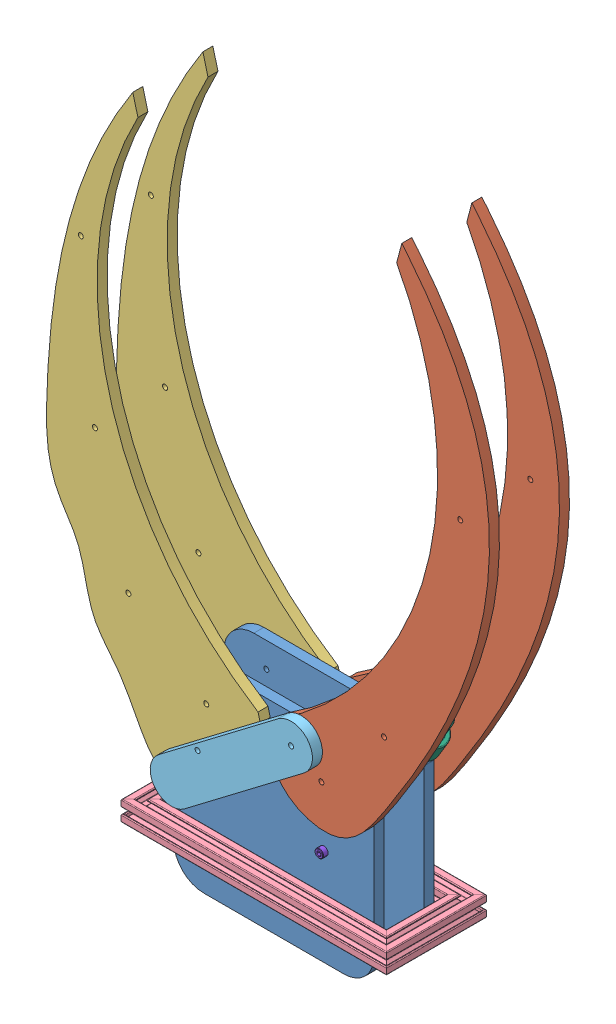
SolidWorks assembly claw complete, configuration Default. Lengths in mm.
Overall size (614.17 674.27 100).
12 component instances, 8 part files, 24 mates.
Components (placement in the parent):
- base (1)-1: base (1) [Default] at (84.5945 78.7634 160.6694) size (200 200 10)
- left-1: left [Default] at (97.6438 176.1538 100.6694) x (0.967017 -0.254711 0) z (0 0 1) size (196.08 572.16 10)
- right-1: right [Default] at (78.7753 172.5806 100.6694) x (0.966864 0.255292 0) z (0 0 1) size (173.08 567.26 10)
- base (1)-2: base (1) [Default] at (84.5945 78.7634 110.6694) size (200 200 10)
- right-2: right [Default] at (78.7753 172.5806 170.6694) x (0.966864 0.255292 0) z (0 0 1) size (173.08 567.26 10)
- left-2: left [Default] at (97.6438 176.1538 170.6694) x (0.967017 -0.254711 0) z (0 0 1) size (196.08 572.16 10)
- claw support-3: claw support [Default<As Machined>] at (84.5945 28.7634 140.6694) x (-1 0 0) z (0 1 0) size (265 100 20)
- claw motion-1: claw motion [Default] at (64.7629 126.4273 180.6694) x (0.79619 0.605047 0) z (0 0 1) size (192.73 42.73 10)
- cylinder assembly-1: cylinder assembly [Default] at (148.8168 100.0117 48.5018) x (0 0 -1) z (0.516333 0.856388 0) size (30 32.55 195)
  - cylinder-1: cylinder [Default] at (-92.1798 -0.5475 141.514) size (30 32.55 185)
  - cylinder rod-1: cylinder rod [Default] at (-92.1798 -0.5475 51.514) x (0.995961 0.089791 0) z (0.089791 -0.995961 0) size (10 100 10)
- socket head cap screw_am-1: socket head cap screw_am [B18.3.1M - 5 x 0.8 x 70 Hex SHCS -- 22NHX] at (134.5775 75.334 175.6694) x (0 0 -1) z (0.998896 -0.046986 0) size (75 8.5 8.5)
Mates (geometry in assembly coordinates):
- Distance3: distance = 40 mm aligned: plane of claw support-3 through (-37.9055 18.7634 184.4694) normal (0 -1 0); plane of base (1)-2 through (14.5945 -21.2366 120.6694) normal (0 -1 0)
- Concentric17: concentric aligned: cylinder of left-2 through (121.8192 169.786 180.6694) axis (0 0 -1) radius 2.5; cylinder of claw motion-1 through (121.8192 169.786 190.6694) axis (0 0 -1) radius 2.5
- Concentric18: concentric aligned: cylinder of right-2 through (28.4116 119.0557 180.6694) axis (0 0 -1) radius 2.5; cylinder of claw motion-1 through (28.4116 119.0557 190.6694) axis (0 0 -1) radius 2.5
- Coincident13: coincident anti-aligned: plane of right-2 through (262.9987 464.277 180.6694) normal (0 0 1); plane of claw motion-1 through (2.3907 79.029 180.6694) normal (0 0 -1)
- Coincident14: coincident anti-aligned: plane of left-2 through (289.7572 315.3858 180.6694) normal (0 0 1); plane of claw motion-1 through (2.3907 79.029 180.6694) normal (0 0 -1)
- Coincident15: coincident anti-aligned: plane of base (1)-1 through (14.5945 8.7634 170.6694) normal (0 0 1); plane of claw support-3 through (-37.9055 24.9634 170.6694) normal (0 0 -1)
- Coincident20: coincident anti-aligned: plane of base (1)-1 through (14.5945 8.7634 170.6694) normal (0 0 1); plane of left-2 through (289.7572 315.3858 170.6694) normal (0 0 -1)
- Concentric19: concentric aligned: cylinder of base (1)-1 through (142.0945 143.7634 170.6694) axis (0 0 -1) radius 2.5; cylinder of left-2 through (142.0945 143.7634 180.6694) axis (0 0 -1) radius 2.5
- Concentric20: concentric aligned: cylinder of base (1)-1 through (27.0945 153.7634 170.6694) axis (0 0 -1) radius 2.5; cylinder of right-2 through (27.0945 153.7634 180.6694) axis (0 0 -1) radius 2.5
- Concentric21: concentric aligned: cylinder of right-1 through (-50.7146 210.5898 110.6694) axis (0 0 -1) radius 2.5; cylinder of right-2 through (-50.7146 210.5898 180.6694) axis (0 0 -1) radius 2.5
- Concentric22: concentric aligned: cylinder of right-1 through (-84.1373 337.1715 110.6694) axis (0 0 -1) radius 2.5; cylinder of right-2 through (-84.1373 337.1715 180.6694) axis (0 0 -1) radius 2.5
- Concentric23: concentric aligned: cylinder of left-1 through (280.8661 439.9001 110.6694) axis (0 0 -1) radius 2.5; cylinder of left-2 through (280.8661 439.9001 180.6694) axis (0 0 -1) radius 2.5
- Concentric24: concentric aligned: cylinder of left-1 through (142.0945 143.7634 110.6694) axis (0 0 -1) radius 2.5; cylinder of base (1)-2 through (142.0945 143.7634 120.6694) axis (0 0 -1) radius 2.5
- Coincident23: coincident anti-aligned: plane of base (1)-2 through (14.5945 8.7634 110.6694) normal (0 0 -1); plane of claw support-3 through (-37.9055 37.9634 110.6694) normal (0 0 1)
- Width1: width anti-aligned: plane of claw support-3 through (197.0945 24.9634 180.6694) normal (-1 0 0); plane of claw support-3 through (-27.9055 24.9634 180.6694) normal (1 0 0); plane of base (1)-1 through (184.5945 8.7634 170.6694) normal (1 0 0); plane of base (1)-1 through (-15.4055 8.7634 170.6694) normal (-1 0 0)
- Concentric25: concentric aligned: cylinder of base (1)-1 through (134.5775 75.334 170.6694) axis (0 0 -1) radius 4; cylinder of base (1)-2 through (134.5775 75.334 120.6694) axis (0 0 -1) radius 4
- Concentric26: concentric aligned: cylinder of base (1)-1 through (134.5775 75.334 170.6694) axis (0 0 -1) radius 4; cylinder of cylinder assembly-1/cylinder-1 through (134.5775 75.334 155.6816) axis (0 0 -1) radius 4
- Width2: width aligned: plane of cylinder assembly-1/cylinder-1 through (134.5775 75.334 148.1816) normal (0 0 1); plane of cylinder assembly-1/cylinder-1 through (134.5775 75.334 133.1572) normal (0 0 -1); plane of base (1)-2 through (14.5945 8.7634 120.6694) normal (0 0 1); plane of base (1)-1 through (14.5945 8.7634 160.6694) normal (0 0 -1)
- Coincident24: coincident anti-aligned: plane of right-1 through (262.9987 464.277 110.6694) normal (0 0 1); plane of base (1)-2 through (14.5945 8.7634 110.6694) normal (0 0 -1)
- Coincident25: coincident anti-aligned: plane of left-1 through (289.7572 315.3858 110.6694) normal (0 0 1); plane of base (1)-2 through (14.5945 8.7634 110.6694) normal (0 0 -1)
- Concentric27: concentric anti-aligned: cylinder of base (1)-1 through (134.5775 75.334 170.6694) axis (0 0 -1) radius 4; cylinder of socket head cap screw_am-1 through (134.5775 75.334 207.4194) axis (0 0 1) radius 4.25
- Coincident26: coincident anti-aligned: plane of base (1)-1 through (14.5945 8.7634 170.6694) normal (0 0 1); plane of socket head cap screw_am-1 through (134.7772 79.5793 170.6694) normal (0 0 -1)
- Lock1: lock: unknown of cylinder assembly-1/cylinder-1; unknown of socket head cap screw_am-1
- Lock2: lock: unknown of base (1)-1; unknown of cylinder assembly-1/cylinder-1
